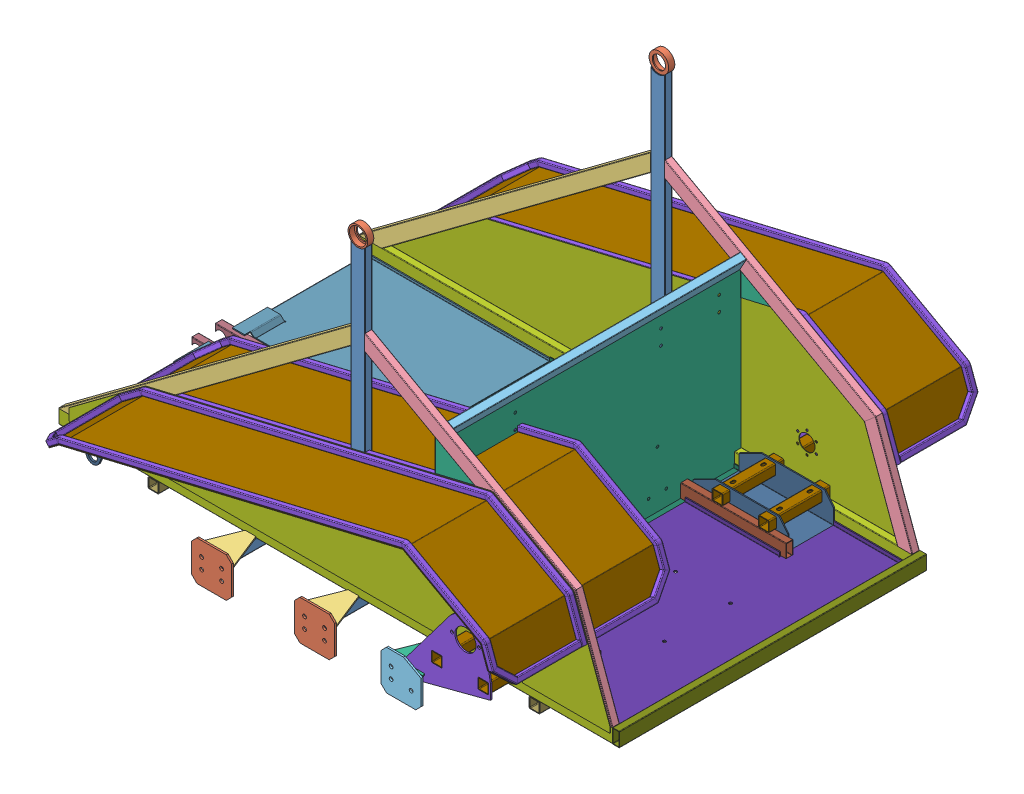
SolidWorks assembly ТП.016.01.00 - Корпус с обвесом, configuration 00. Lengths in mm.
Overall size (1585 1122.78 1359).
94 component instances, 29 part files, 15 mates.
Components (placement in the parent):
- ТП.016.01.01.00 - Корпус-1: ТП.016.01.01.00 - Корпус [00] at origin size (1585 989.69 1098)
  - ТП.016.01.01.01.00 - Рама корпуса-1: ТП.016.01.01.01.00 - Рама корпуса [00] at origin size (1585 284.02 1098)
    - ТП.016.01.01.01.01.00 - Поперечная балка в сборе-1: ТП.016.01.01.01.01.00 - Поперечная балка в сборе [Центральная] at (824.8534 -30 544) size (112 110.77 1078)
      - ТП.016.01.01.01.01.01 - Поперечная балка (30х30)-1: ТП.016.01.01.01.01.01 - Поперечная балка (30х30) [--] at origin size (30 30 1068)
      - ТП.016.01.01.01.01.02 - Пластина кронштейна (5мм)-1: ТП.016.01.01.01.01.02 - Пластина кронштейна (5мм) [--] at (0 -56.7738 -5) size (112 110.77 5)
      - ТП.016.01.01.01.01.03 - Косынка верхняя (4мм)-1: ТП.016.01.01.01.01.03 - Косынка верхняя (4мм) [--] at (0 30 -10) size (112 4 104)
      - ТП.016.01.01.01.01.02 - Пластина кронштейна (5мм)-2: ТП.016.01.01.01.01.02 - Пластина кронштейна (5мм) [--] at (0 -56.7738 -1083) x (-1 0 0) z (0 0 -1) size (112 110.77 5)
      - ТП.016.01.01.01.01.03 - Косынка верхняя (4мм)-2: ТП.016.01.01.01.01.03 - Косынка верхняя (4мм) [--] at (0 30 -1078) x (-1 0 0) z (0 0 -1) size (112 4 104)
      - ТП.016.01.01.01.01.04 - Косынка нижняя (4мм)-2: ТП.016.01.01.01.01.04 - Косынка нижняя (4мм) [--] at (0 0 -1078) x (-1 0 0) z (0 0 -1) size (4 53.77 53.77)
      - ТП.016.01.01.01.01.04 - Косынка нижняя (4мм)-3: ТП.016.01.01.01.01.04 - Косынка нижняя (4мм) [--] at (0 0 -10) size (4 53.77 53.77)
      - ТП.016.01.01.01.01.05 - Пластина кронштейна задняя (5мм)-1: ТП.016.01.01.01.01.05 - Пластина кронштейна задняя (5мм) [--] at (0 -56.7738 -1083) x (-1 0 0) z (0 0 -1) size (112 110.77 5) (hidden)
      - ТП.016.01.01.01.01.06 - Косынка верхняя задняя (4мм)-1: ТП.016.01.01.01.01.06 - Косынка верхняя задняя (4мм) [--] at (-15 30 -1078) x (-1 0 0) z (0 0 -1) size (111.99 4 104) (hidden)
      - ТП.016.01.01.01.01.05 - Пластина кронштейна задняя (5мм)-2: ТП.016.01.01.01.01.05 - Пластина кронштейна задняя (5мм) [--] at (0 -56.7738 -10) x (-1 0 0) z (0 0 -1) size (112 110.77 5) (hidden)
      - ТП.016.01.01.01.01.06 - Косынка верхняя задняя (4мм)-2: ТП.016.01.01.01.01.06 - Косынка верхняя задняя (4мм) [--] at (-15 34 -10) x (-1 0 0) z (0 0 1) size (111.99 4 104) (hidden)
    - ТП.016.01.01.01.01.00 - Поперечная балка в сборе-2: ТП.016.01.01.01.01.00 - Поперечная балка в сборе [Центральная] at (536.5267 -30 544) size (112 110.77 1078)
      - ТП.016.01.01.01.01.01 - Поперечная балка (30х30)-1: ТП.016.01.01.01.01.01 - Поперечная балка (30х30) [--] at origin size (30 30 1068)
      - ТП.016.01.01.01.01.02 - Пластина кронштейна (5мм)-1: ТП.016.01.01.01.01.02 - Пластина кронштейна (5мм) [--] at (0 -56.7738 -5) size (112 110.77 5)
      - ТП.016.01.01.01.01.03 - Косынка верхняя (4мм)-1: ТП.016.01.01.01.01.03 - Косынка верхняя (4мм) [--] at (0 30 -10) size (112 4 104)
      - ТП.016.01.01.01.01.02 - Пластина кронштейна (5мм)-2: ТП.016.01.01.01.01.02 - Пластина кронштейна (5мм) [--] at (0 -56.7738 -1083) x (-1 0 0) z (0 0 -1) size (112 110.77 5)
      - ТП.016.01.01.01.01.03 - Косынка верхняя (4мм)-2: ТП.016.01.01.01.01.03 - Косынка верхняя (4мм) [--] at (0 30 -1078) x (-1 0 0) z (0 0 -1) size (112 4 104)
      - ТП.016.01.01.01.01.04 - Косынка нижняя (4мм)-2: ТП.016.01.01.01.01.04 - Косынка нижняя (4мм) [--] at (0 0 -1078) x (-1 0 0) z (0 0 -1) size (4 53.77 53.77)
      - ТП.016.01.01.01.01.04 - Косынка нижняя (4мм)-3: ТП.016.01.01.01.01.04 - Косынка нижняя (4мм) [--] at (0 0 -10) size (4 53.77 53.77)
      - ТП.016.01.01.01.01.05 - Пластина кронштейна задняя (5мм)-1: ТП.016.01.01.01.01.05 - Пластина кронштейна задняя (5мм) [--] at (0 -56.7738 -1083) x (-1 0 0) z (0 0 -1) size (112 110.77 5) (hidden)
      - ТП.016.01.01.01.01.06 - Косынка верхняя задняя (4мм)-1: ТП.016.01.01.01.01.06 - Косынка верхняя задняя (4мм) [--] at (-15 30 -1078) x (-1 0 0) z (0 0 -1) size (111.99 4 104) (hidden)
      - ТП.016.01.01.01.01.05 - Пластина кронштейна задняя (5мм)-2: ТП.016.01.01.01.01.05 - Пластина кронштейна задняя (5мм) [--] at (0 -56.7738 -10) x (-1 0 0) z (0 0 -1) size (112 110.77 5) (hidden)
      - ТП.016.01.01.01.01.06 - Косынка верхняя задняя (4мм)-2: ТП.016.01.01.01.01.06 - Косынка верхняя задняя (4мм) [--] at (-15 34 -10) x (-1 0 0) z (0 0 1) size (111.99 4 104) (hidden)
    - ТП.016.01.01.01.01.00 - Поперечная балка в сборе-3: ТП.016.01.01.01.01.00 - Поперечная балка в сборе [Задняя] at (1067.2668 -30 544) size (112 110.77 1078)
      - ТП.016.01.01.01.01.01 - Поперечная балка (30х30)-1: ТП.016.01.01.01.01.01 - Поперечная балка (30х30) [Под лебедку] at origin size (30 30 1068)
      - ТП.016.01.01.01.01.02 - Пластина кронштейна (5мм)-1: ТП.016.01.01.01.01.02 - Пластина кронштейна (5мм) [--] at (0 -56.7738 -5) size (112 110.77 5) (hidden)
      - ТП.016.01.01.01.01.03 - Косынка верхняя (4мм)-1: ТП.016.01.01.01.01.03 - Косынка верхняя (4мм) [--] at (0 30 -10) size (112 4 104) (hidden)
      - ТП.016.01.01.01.01.02 - Пластина кронштейна (5мм)-2: ТП.016.01.01.01.01.02 - Пластина кронштейна (5мм) [--] at (0 -56.7738 -1083) x (-1 0 0) z (0 0 -1) size (112 110.77 5) (hidden)
      - ТП.016.01.01.01.01.03 - Косынка верхняя (4мм)-2: ТП.016.01.01.01.01.03 - Косынка верхняя (4мм) [--] at (0 30 -1078) x (-1 0 0) z (0 0 -1) size (112 4 104) (hidden)
      - ТП.016.01.01.01.01.04 - Косынка нижняя (4мм)-2: ТП.016.01.01.01.01.04 - Косынка нижняя (4мм) [--] at (0 0 -1078) x (-1 0 0) z (0 0 -1) size (4 53.77 53.77)
      - ТП.016.01.01.01.01.04 - Косынка нижняя (4мм)-3: ТП.016.01.01.01.01.04 - Косынка нижняя (4мм) [--] at (0 0 -10) size (4 53.77 53.77)
      - ТП.016.01.01.01.01.05 - Пластина кронштейна задняя (5мм)-1: ТП.016.01.01.01.01.05 - Пластина кронштейна задняя (5мм) [--] at (0 -56.7738 -1083) x (-1 0 0) z (0 0 -1) size (112 110.77 5)
      - ТП.016.01.01.01.01.06 - Косынка верхняя задняя (4мм)-1: ТП.016.01.01.01.01.06 - Косынка верхняя задняя (4мм) [--] at (-15 30 -1078) x (-1 0 0) z (0 0 -1) size (111.99 4 104)
      - ТП.016.01.01.01.01.05 - Пластина кронштейна задняя (5мм)-2: ТП.016.01.01.01.01.05 - Пластина кронштейна задняя (5мм) [--] at (0 -56.7738 -10) x (-1 0 0) z (0 0 -1) size (112 110.77 5)
      - ТП.016.01.01.01.01.06 - Косынка верхняя задняя (4мм)-2: ТП.016.01.01.01.01.06 - Косынка верхняя задняя (4мм) [--] at (-15 34 -10) x (-1 0 0) z (0 0 1) size (111.99 4 104)
    - ТП.016.01.01.01.02 - Балка платформы боковая (40х20)-1: ТП.016.01.01.01.02 - Балка платформы боковая (40х20) [--] at (250 0 -420) x (0 0 -1) z (1 0 0) size (20 40 1550)
    - ТП.016.01.01.01.02 - Балка платформы боковая (40х20)-2: ТП.016.01.01.01.02 - Балка платформы боковая (40х20) [--] at (250 0 420) x (0 0 -1) z (1 0 0) size (20 40 1550)
    - Схема рамы ЭСКИЗ-1: Схема рамы ЭСКИЗ [--] x (0 0 -1) z (1 0 0) size (559 0 1052.27)
    - ТП.016.01.01.01.03.00 - Опора редуктора-1: ТП.016.01.01.01.03.00 - Опора редуктора [Правая] at (1235 143.2262 -526.5) x (-1 0 0) z (0 0 -1) size (276.73 227.25 267.34)
      - ТП.016.01.01.01.03.01 - Щека ведущей оси (4мм)-1: ТП.016.01.01.01.03.01 - Щека ведущей оси (4мм) [--] at origin size (249.73 227.25 4)
      - ТП.016.01.01.01.03.02 - Балка опоры ребуктора (30х30)-1: ТП.016.01.01.01.03.02 - Балка опоры ребуктора (30х30) [--] at (65 -72 0) size (30 30 267.34)
      - ТП.016.01.01.01.03.02 - Балка опоры ребуктора (30х30)-2: ТП.016.01.01.01.03.02 - Балка опоры ребуктора (30х30) [--] at (-65 -72 0) size (30 30 267.34)
      - ТП.016.01.01.01.03.02 - Балка опоры ребуктора (30х30)-3: ТП.016.01.01.01.03.02 - Балка опоры ребуктора (30х30) [--] at (95 -72 -4) x (-1 0 0) z (0 0 -1) size (30 30 267.34) (hidden)
      - ТП.016.01.01.01.03.02 - Балка опоры ребуктора (30х30)-4: ТП.016.01.01.01.03.02 - Балка опоры ребуктора (30х30) [--] at (-35 -72 -4) x (-1 0 0) z (0 0 -1) size (30 30 267.34) (hidden)
      - ТП.016.01.01.01.03.03 - Пол под редуктор (3мм)-1: ТП.016.01.01.01.03.03 - Пол под редуктор (3мм) [--] at (65 -143.2262 -181.9182) x (0 0 -1) z (1 0 0) size (130.84 76.23 264.73)
    - ТП.016.01.01.01.03.00 - Опора редуктора-2: ТП.016.01.01.01.03.00 - Опора редуктора [Левая] at (1235 143.2262 522.5) x (-1 0 0) z (0 0 -1) size (276.73 227.25 267.34)
      - ТП.016.01.01.01.03.01 - Щека ведущей оси (4мм)-1: ТП.016.01.01.01.03.01 - Щека ведущей оси (4мм) [--] at origin size (249.73 227.25 4)
      - ТП.016.01.01.01.03.02 - Балка опоры ребуктора (30х30)-1: ТП.016.01.01.01.03.02 - Балка опоры ребуктора (30х30) [--] at (65 -72 0) size (30 30 267.34) (hidden)
      - ТП.016.01.01.01.03.02 - Балка опоры ребуктора (30х30)-2: ТП.016.01.01.01.03.02 - Балка опоры ребуктора (30х30) [--] at (-65 -72 0) size (30 30 267.34) (hidden)
      - ТП.016.01.01.01.03.02 - Балка опоры ребуктора (30х30)-3: ТП.016.01.01.01.03.02 - Балка опоры ребуктора (30х30) [--] at (95 -72 -4) x (-1 0 0) z (0 0 -1) size (30 30 267.34)
      - ТП.016.01.01.01.03.02 - Балка опоры ребуктора (30х30)-4: ТП.016.01.01.01.03.02 - Балка опоры ребуктора (30х30) [--] at (-35 -72 -4) x (-1 0 0) z (0 0 -1) size (30 30 267.34)
      - ТП.016.01.01.01.03.03 - Пол под редуктор (3мм)-1: ТП.016.01.01.01.03.03 - Пол под редуктор (3мм) [--] at (65 -143.2262 177.9182) x (0 0 -1) z (1 0 0) size (130.84 76.23 264.73)
    - ТП.016.01.01.01.04 - Опора короткая под редуктор (40х20)-1: ТП.016.01.01.01.04 - Опора короткая под редуктор (40х20) [--] at (1052.2668 0 -259.1637) x (0 0 -1) z (1 0 0) size (20 40 294.73)
    - ТП.016.01.01.01.04 - Опора короткая под редуктор (40х20)-2: ТП.016.01.01.01.04 - Опора короткая под редуктор (40х20) [--] at (1052.2668 0 279.1637) x (0 0 -1) z (1 0 0) size (20 40 294.73)
    - ТП.016.01.01.01.05 - Поперечина короткая (30х30)-1: ТП.016.01.01.01.05 - Поперечина короткая (30х30) [--] at (1347 0 0) size (30 30 860)
    - ТП.016.01.01.01.05 - Поперечина короткая (30х30)-2: ТП.016.01.01.01.05 - Поперечина короткая (30х30) [--] at (280 0 0) size (30 30 860)
    - ТП.016.01.01.01.06 - Поддержка центральная (40х20)-1: ТП.016.01.01.01.06 - Поддержка центральная (40х20) [--] at (45 -9.1741 -23) x (0 0 1) z (-1 0 0) size (20 40 596.53)
    - ТП.016.01.01.01.06 - Поддержка центральная (40х20)-2: ТП.016.01.01.01.06 - Поддержка центральная (40х20) [--] at (45 -9.1741 43) x (0 0 1) z (-1 0 0) size (20 40 596.53)
    - ТП.016.01.01.01.07 - Пол перед (3мм)-1: ТП.016.01.01.01.07 - Пол перед (3мм) [Правый] at (0 0 -410) x (0 0 -1) z (1 0 0) size (377 29.49 517.11)
    - ТП.016.01.01.01.07 - Пол перед (3мм)-2: ТП.016.01.01.01.07 - Пол перед (3мм) [Левый] at (0 0 -344) x (0 0 -1) z (1 0 0) size (754 29.49 517.11)
    - ТП.016.01.01.01.08 - Пол центр (2мм)-1: ТП.016.01.01.01.08 - Пол центр (2мм) [--] at (250 0 0) x (0 0 -1) z (1 0 0) size (820 12 817.27)
    - ТП.016.01.01.01.09 - Задний бампер (40х20)-1: ТП.016.01.01.01.09 - Задний бампер (40х20) [--] at (1570 0 0) size (20 40 860)
    - ТП.016.01.01.01.10 - Пол капота (3мм)-1: ТП.016.01.01.01.10 - Пол капота (3мм) [--] at (1550 0 0) x (0 0 1) z (-1 0 0) size (820 13 482.73)
    - Гайка (ГОСТ ISO 4032-2014)-1: Гайка (ГОСТ ISO 4032-2014) [Гайка М6 (ГОСТ ISO 4032)] at (153.1386 -2.6 64.0253) x (-0.998033 0 -0.062689) z (0 1 0) size (10 11.05 5.2)
    - Гайка (ГОСТ ISO 4032-2014)-2: Гайка (ГОСТ ISO 4032-2014) [Гайка М6 (ГОСТ ISO 4032)] at (403.0634 -2.6 70.156) x (-0.991964 0 0.126519) z (0 1 0) size (10 11.05 5.2)
    - Гайка (ГОСТ ISO 4032-2014)-3: Гайка (ГОСТ ISO 4032-2014) [Гайка М6 (ГОСТ ISO 4032)] at (672.9822 -2.6 76.7772) x (-0.941367 0 0.337385) z (0 1 0) size (10 11.05 5.2)
    - Гайка (ГОСТ ISO 4032-2014)-4: Гайка (ГОСТ ISO 4032-2014) [Гайка М6 (ГОСТ ISO 4032)] at (1021.6211 -2.6 85.3294) x (-0.83604 0 0.548669) z (0 1 0) size (10 11.05 5.2)
    - Гайка (ГОСТ ISO 4032-2014)-5: Гайка (ГОСТ ISO 4032-2014) [Гайка М6 (ГОСТ ISO 4032)] at (1021.6211 -2.6 -85.3294) x (-0.680834 0 0.732437) z (0 1 0) size (10 11.05 5.2)
    - Гайка (ГОСТ ISO 4032-2014)-6: Гайка (ГОСТ ISO 4032-2014) [Гайка М6 (ГОСТ ISO 4032)] at (672.9822 -2.6 -76.7772) x (-0.498939 0 0.866637) z (0 1 0) size (10 11.05 5.2)
    - Гайка (ГОСТ ISO 4032-2014)-7: Гайка (ГОСТ ISO 4032-2014) [Гайка М6 (ГОСТ ISO 4032)] at (403.0634 -2.6 -70.156) x (-0.323185 0 0.946336) z (0 1 0) size (10 11.05 5.2)
    - Гайка (ГОСТ ISO 4032-2014)-8: Гайка (ГОСТ ISO 4032-2014) [Гайка М6 (ГОСТ ISO 4032)] at (153.1386 -2.6 -64.0253) x (-0.182176 0 0.983266) z (0 1 0) size (10 11.05 5.2)
  - ТП.016.01.01.02.00 - Вертикальная опора рычага-1: ТП.016.01.01.02.00 - Вертикальная опора рычага [00] at (837.2668 40 -410) x (0 0 -1) z (1 0 0) size (20 865.92 61.84)
    - ТП.016.01.01.02.01 - Вертикальная поддержка оси защиты (40х20)-1: ТП.016.01.01.02.01 - Вертикальная поддержка оси защиты (40х20) [--] at origin size (20 816.26 40)
    - ТП.016.01.01.02.02 - Обойма оси рычага-1: ТП.016.01.01.02.02 - Обойма оси рычага [--] at (20 835 0) x (1 0 0) z (0 -0.133324 -0.991073) size (17 55 55)
  - ТП.016.01.01.03 - Фронтальная наклонная поддержка (40х20)-1: ТП.016.01.01.03 - Фронтальная наклонная поддержка (40х20) [--] at (817.2668 40 -428.5) x (-1 0 0) z (0 0 -1) size (842.66 642.08 20)
  - ТП.016.01.01.04 - Задняя наклонная поддержка (40х20)-1: ТП.016.01.01.04 - Задняя наклонная поддержка (40х20) [--] at (857.2668 40 -428.5) x (-1 0 0) z (0 0 -1) size (694.23 610.67 20)
  - ТП.016.01.01.04 - Задняя наклонная поддержка (40х20)-2: ТП.016.01.01.04 - Задняя наклонная поддержка (40х20) [--] at (857.2668 40 411.5) x (-1 0 0) z (0 0 -1) size (694.23 610.67 20)
  - ТП.016.01.01.03 - Фронтальная наклонная поддержка (40х20)-2: ТП.016.01.01.03 - Фронтальная наклонная поддержка (40х20) [--] at (817.2668 40 411.5) x (-1 0 0) z (0 0 -1) size (842.66 642.08 20)
  - ТП.016.01.01.02.00 - Вертикальная опора рычага-2: ТП.016.01.01.02.00 - Вертикальная опора рычага [00] at (837.2668 40 410) x (0 0 1) z (-1 0 0) size (20 865.92 61.84)
    - ТП.016.01.01.02.01 - Вертикальная поддержка оси защиты (40х20)-1: ТП.016.01.01.02.01 - Вертикальная поддержка оси защиты (40х20) [--] at origin size (20 816.26 40)
    - ТП.016.01.01.02.02 - Обойма оси рычага-1: ТП.016.01.01.02.02 - Обойма оси рычага [--] at (20 835 0) x (1 0 0) z (0 -0.133324 -0.991073) size (17 55 55)
  - ТП.016.01.01.05 - Поперечина между бортами верхняя (40х20)-1: ТП.016.01.01.05 - Поперечина между бортами верхняя (40х20) [--] at (1098.7044 515.2767 410) x (0.874527 -0.484977 0) z (0 0 1) size (20 40 820)
  - ТП.016.01.01.06 - Стенка моторного отсека (1_5мм)-1: ТП.016.01.01.06 - Стенка моторного отсека (1_5мм) [--] at (1052.2668 0 0) x (0 0 -1) z (1 0 0) size (857 493.29 116.33)
  - ТП.016.01.01.07 - Бок корпуса (1_5мм)-2: ТП.016.01.01.07 - Бок корпуса (1_5мм) [--] at (817.2668 40 -430) x (-1 0 0) z (0 0 -1) size (1514.68 420.65 1.5)
  - ТП.016.01.01.07 - Бок корпуса (1_5мм)-3: ТП.016.01.01.07 - Бок корпуса (1_5мм) [--] at (817.2668 40 431.5) x (-1 0 0) z (0 0 -1) size (1514.68 420.65 1.5)
- ТП.016.01.02 - Рамка крыла-1: ТП.016.01.02 - Рамка крыла [Правая] at (1468.7791 204.6765 -431.5) x (0 0 1) z (-0.34202 0.939693 0) size (248 1247.49 428.39)
- ТП.016.01.03 - Крыло (1_5мм)-1: ТП.016.01.03 - Крыло (1_5мм) [Левое] at (837.2668 40 -431.5) x (-1 0 0) z (0 0 -1) size (1287.68 280.37 248)
- ТП.016.01.04 - Ухо оси навески (5мм)-1: ТП.016.01.04 - Ухо оси навески (5мм) [--] at (100 40 -435) size (80 83 5)
- ТП.016.01.04 - Ухо оси навески (5мм)-2: ТП.016.01.04 - Ухо оси навески (5мм) [--] at (100 40 430) size (80 83 5)
- ТП.016.01.02 - Рамка крыла-2: ТП.016.01.02 - Рамка крыла [Левая] at (1468.7791 204.6765 431.5) x (0 0 1) z (-0.34202 0.939693 0) size (496 1247.49 428.39)
- ТП.016.01.03 - Крыло (1_5мм)-2: ТП.016.01.03 - Крыло (1_5мм) [Правое] at (837.2668 40 431.5) x (-1 0 0) z (0 0 -1) size (1287.68 280.37 496)
Mates (geometry in assembly coordinates):
- Совпадение1: coincident: plane of ТП.016.01.01.00 - Корпус-1/ТП.016.01.01.07 - Бок корпуса (1_5мм)-2 through (1143 68.2262 -431.5) normal (0 0 -1); plane of ТП.016.01.02 - Рамка крыла-1 through (1431.5159 310.4164 -431.5) normal (0 0 1)
- Совпадение2: coincident: plane of ТП.016.01.01.00 - Корпус-1/ТП.016.01.01.07 - Бок корпуса (1_5мм)-2 through (1208.2182 443.6815 -431.5) normal (-0.23083 0.972994 0); plane of ТП.016.01.02 - Рамка крыла-1 through (1208.2182 443.6815 -444.25) normal (-0.23083 0.972994 0)
- Совпадение3: coincident: plane of ТП.016.01.01.00 - Корпус-1/ТП.016.01.01.07 - Бок корпуса (1_5мм)-2 through (239.9284 212.5171 -431.5) normal (-0.597443 0.801912 0); plane of ТП.016.01.02 - Рамка крыла-1 through (239.9284 212.5171 -444.25) normal (-0.597443 0.801912 0)
- Совпадение4: coincident: plane of ТП.016.01.01.00 - Корпус-1/ТП.016.01.01.07 - Бок корпуса (1_5мм)-2 through (1143 68.2262 -431.5) normal (0 0 -1); plane of ТП.016.01.03 - Крыло (1_5мм)-1 through (249.7862 199.2855 -431.5) normal (0 0 1)
- Совпадение5: coincident: plane of ТП.016.01.02 - Рамка крыла-1 through (1430.4247 308.4487 -444.25) normal (-0.484977 -0.874527 0); plane of ТП.016.01.03 - Крыло (1_5мм)-1 through (1431.1569 308.0427 -1997.3495) normal (0.484977 0.874527 0)
- Совпадение6: coincident: plane of ТП.016.01.02 - Рамка крыла-1 through (1211.6807 429.0866 -444.25) normal (0.23083 -0.972994 0); plane of ТП.016.01.03 - Крыло (1_5мм)-1 through (1212.5251 429.2869 -1997.3495) normal (-0.23083 0.972994 0)
- Совпадение7: coincident: plane of ТП.016.01.01.00 - Корпус-1/ТП.016.01.01.01.00 - Рама корпуса-1/ТП.016.01.01.01.02 - Балка платформы боковая (40х20)-1 through (0 38.5 -430) normal (0 0 -1); plane of ТП.016.01.04 - Ухо оси навески (5мм)-1 through (100 -25 -430) normal (0 0 1)
- Совпадение8: coincident: plane of ТП.016.01.01.00 - Корпус-1/ТП.016.01.01.07 - Бок корпуса (1_5мм)-2 through (60 38.5 -431.5) normal (0 -1 0); plane of ТП.016.01.04 - Ухо оси навески (5мм)-1 through (60 38.5 -430) normal (0 1 0)
- Совпадение9: coincident: plane of ТП.016.01.01.00 - Корпус-1/ТП.016.01.01.07 - Бок корпуса (1_5мм)-2 through (60 23.5 -431.5) normal (1 0 0); plane of ТП.016.01.04 - Ухо оси навески (5мм)-1 through (60 23.5 -430) normal (-1 0 0)
- Совпадение10: coincident: plane of ТП.016.01.01.00 - Корпус-1/ТП.016.01.01.07 - Бок корпуса (1_5мм)-3 through (1143 68.2262 431.5) normal (0 0 1); plane of ТП.016.01.02 - Рамка крыла-2 through (1431.5159 310.4164 431.5) normal (0 0 -1)
- Совпадение11: coincident: plane of ТП.016.01.02 - Рамка крыла-1 through (1208.2182 443.6815 -444.25) normal (-0.23083 0.972994 0); plane of ТП.016.01.02 - Рамка крыла-2 through (1208.2182 443.6815 444.25) normal (-0.23083 0.972994 0)
- Совпадение12: coincident: plane of ТП.016.01.02 - Рамка крыла-1 through (1437.6993 321.5667 -444.25) normal (0.484977 0.874527 0); plane of ТП.016.01.02 - Рамка крыла-2 through (1437.6993 321.5667 444.25) normal (0.484977 0.874527 0)
- Совпадение13: coincident: plane of ТП.016.01.01.00 - Корпус-1/ТП.016.01.01.07 - Бок корпуса (1_5мм)-3 through (1143 68.2262 431.5) normal (0 0 1); plane of ТП.016.01.03 - Крыло (1_5мм)-2 through (249.7862 199.2855 431.5) normal (0 0 -1)
- Совпадение14: coincident: plane of ТП.016.01.03 - Крыло (1_5мм)-1 through (1212.5251 429.2869 -1997.3495) normal (-0.23083 0.972994 0); plane of ТП.016.01.03 - Крыло (1_5мм)-2 through (1212.5251 429.2869 1997.3495) normal (-0.23083 0.972994 0)
- Совпадение15: coincident: plane of ТП.016.01.03 - Крыло (1_5мм)-1 through (1431.1569 308.0427 -1997.3495) normal (0.484977 0.874527 0); plane of ТП.016.01.03 - Крыло (1_5мм)-2 through (1431.1569 308.0427 1997.3495) normal (0.484977 0.874527 0)
